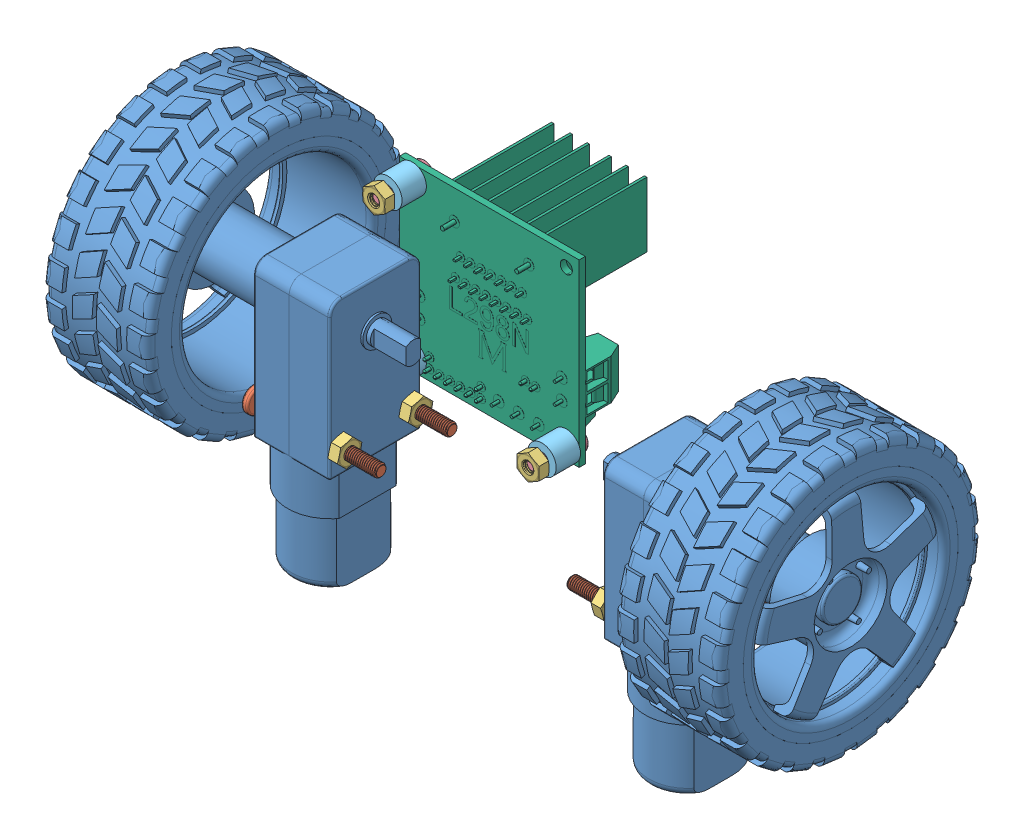
SolidWorks assembly CC, configuration Predeterminado. Lengths in mm.
Overall size (167.22 100.48 92.74).
23 component instances, 6 part files, 10 mates.
Components (placement in the parent):
- smart_car_motor-7: smart_car_motor [Predeterminado] at (215.687 -153.6759 129.1904) x (1 0 0) z (0 -0.96637 0.257157) size (60.29 65 86.68)
  - dc_motor_with_wheel-1: dc_motor_with_wheel [Défaut] at (-4.5268 10.254 22.8405) size (59.31 65 86.68)
  - (M3_30_mm)_90116A155_METRIC 316 SS PAN HEAD PHILLIPS MACHINE SCREW-1: (M3_30_mm)_90116A155_METRIC 316 SS PAN HEAD PHILLIPS MACHINE SCREW [90116A155] at (-42.5488 8.3322 97.9978) x (0 0 -1) z (1 0 0) size (6 6 32.68)
  - (M3_30_mm)_90116A155_METRIC 316 SS PAN HEAD PHILLIPS MACHINE SCREW-2: (M3_30_mm)_90116A155_METRIC 316 SS PAN HEAD PHILLIPS MACHINE SCREW [90116A155] at (-42.5488 -8.5793 93.4976) x (0 0 -1) z (1 0 0) size (6 6 32.68)
  - M3 Nut-1: M3 Nut [Predeterminado] at (-30.8488 8.3322 97.9978) x (0 0 -1) z (1 0 0) size (6.27 6.27 2.71)
  - M3 Nut-2: M3 Nut [Predeterminado] at (-30.8488 -8.5793 93.4976) x (0 0 -1) z (1 0 0) size (6.27 6.27 2.71)
- smart_car_motor-8: smart_car_motor [Predeterminado] at (83.5895 -153.6759 178.196) x (-1 0 0) z (0 -0.96637 -0.257157) size (60.29 65 86.68)
  - dc_motor_with_wheel-1: dc_motor_with_wheel [Défaut] at (-4.5268 10.254 22.8405) size (59.31 65 86.68)
  - (M3_30_mm)_90116A155_METRIC 316 SS PAN HEAD PHILLIPS MACHINE SCREW-1: (M3_30_mm)_90116A155_METRIC 316 SS PAN HEAD PHILLIPS MACHINE SCREW [90116A155] at (-42.5488 8.3322 97.9978) x (0 0 -1) z (1 0 0) size (6 6 32.68)
  - (M3_30_mm)_90116A155_METRIC 316 SS PAN HEAD PHILLIPS MACHINE SCREW-2: (M3_30_mm)_90116A155_METRIC 316 SS PAN HEAD PHILLIPS MACHINE SCREW [90116A155] at (-42.5488 -8.5793 93.4976) x (0 0 -1) z (1 0 0) size (6 6 32.68)
  - M3 Nut-1: M3 Nut [Predeterminado] at (-30.8488 8.3322 97.9978) x (0 0 -1) z (1 0 0) size (6.27 6.27 2.71)
  - M3 Nut-2: M3 Nut [Predeterminado] at (-30.8488 -8.5793 93.4976) x (0 0 -1) z (1 0 0) size (6.27 6.27 2.71)
- L298N_spacer_screwM3-6: L298N_spacer_screwM3 [Predeterminado] at (118.6638 -184.1967 120.4851) x (-1 0 0) z (0 -1 0) size (46.24 12.93 46.24)
  - M3x10 Philips Screw-1: M3x10 Philips Screw [Predeterminado] at (-23.4745 -10.8043 63.32) x (1 0 0) z (0 1 0) size (5.3 5.3 11.8)
  - M3x10 Philips Screw-2: M3x10 Philips Screw [Predeterminado] at (14.5255 -10.8043 63.32) x (1 0 0) z (0 1 0) size (5.3 5.3 11.8)
  - M3x10 Philips Screw-3: M3x10 Philips Screw [Predeterminado] at (14.5255 -10.8043 25.32) x (1 0 0) z (0 1 0) size (5.3 5.3 11.8)
  - separador-1: separador [Predeterminado] at (14.5255 -12.3143 25.32) x (1 0 0) z (0 -1 0) size (7 7 6)
  - M3 Nut-1: M3 Nut [Predeterminado] at (14.5255 -23.3143 25.32) x (1 0 0) z (0 -1 0) size (6.27 6.27 2.71)
  - separador-2: separador [Predeterminado] at (-23.4745 -18.3143 63.32) x (0.472346 0 0.881413) z (0 1 0) size (7 7 6)
  - M3 Nut-2: M3 Nut [Predeterminado] at (-23.4745 -17.8143 63.32) x (1 0 0) z (0 1 0) size (6.27 6.27 2.71)
  - separador-3: separador [Predeterminado] at (14.5255 -12.3143 63.32) x (1 0 0) z (0 -1 0) size (7 7 6)
  - M3 Nut-3: M3 Nut [Predeterminado] at (14.5255 -23.3143 63.32) x (1 0 0) z (0 -1 0) size (6.27 6.27 2.71)
- L298N_M1-3: L298N_M1 [Predeterminado] at (144.6382 -250.3917 132.7994) x (-1 0 0) z (0 -1 0) size (44.32 29.51 44.32)
Mates (geometry in assembly coordinates):
- Coincidente393: coincident: plane of L298N_M1-3 through (100.9782 -250.6767 131.2894) normal (0 0 -1); plane of L298N_spacer_screwM3-6/M3x10 Philips Screw-3 through (104.1382 -207.9167 131.2894) normal (0 0 1)
- Concéntrica246: concentric: circle of L298N_M1-3; circle of L298N_spacer_screwM3-6/M3x10 Philips Screw-3
- Coincidente394: coincident: plane of L298N_M1-3 through (123.1382 -228.5167 132.7994) normal (0 0 1); plane of L298N_spacer_screwM3-6/separador-1 through (104.1382 -209.5167 132.7994) normal (0 0 -1)
- Concéntrica247: concentric: circle of L298N_M1-3; circle of L298N_spacer_screwM3-6/separador-1
- Coincidente395: coincident: plane of L298N_M1-3 through (100.9782 -250.6767 131.2894) normal (0 0 -1); plane of L298N_spacer_screwM3-6/M3x10 Philips Screw-1 through (142.1382 -245.9167 131.2894) normal (0 0 1)
- Coincidente396: coincident: plane of L298N_M1-3 through (123.1382 -228.5167 132.7994) normal (0 0 1); plane of L298N_spacer_screwM3-6/separador-2 through (142.1382 -247.5167 132.7994) normal (0 0 -1)
- Coincidente397: coincident: plane of L298N_M1-3 through (100.9782 -250.6767 131.2894) normal (0 0 -1); plane of L298N_spacer_screwM3-6/M3x10 Philips Screw-2 through (104.1382 -245.9167 131.2894) normal (0 0 1)
- Coincidente398: coincident: plane of L298N_M1-3 through (123.1382 -228.5167 132.7994) normal (0 0 1); plane of L298N_spacer_screwM3-6/separador-3 through (104.1382 -247.5167 132.7994) normal (0 0 -1)
- Concéntrica248: concentric: circle of L298N_M1-3; circle of L298N_spacer_screwM3-6/M3x10 Philips Screw-1
- Concéntrica249: concentric: circle of L298N_M1-3; circle of L298N_spacer_screwM3-6/M3x10 Philips Screw-2
